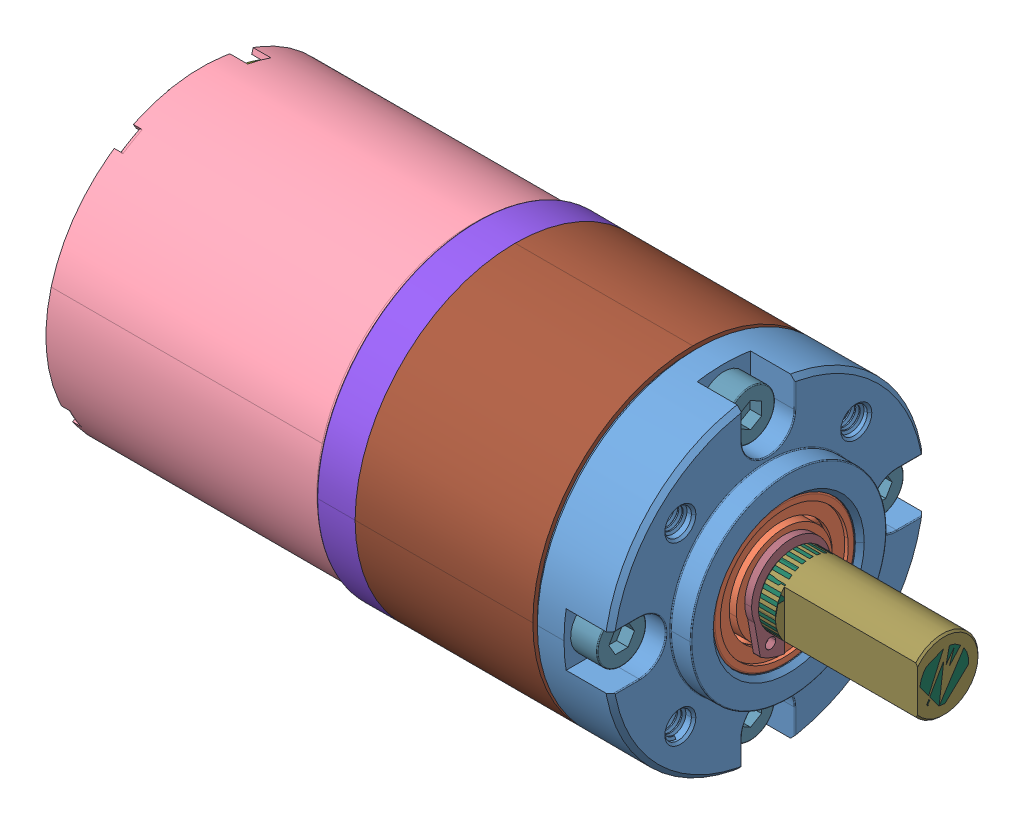
SolidWorks assembly 36GP-3530(L=32.5), configuration 默认. Lengths in mm.
Overall size (89.4 45.32 45.32).
23 component instances, 15 part files, 0 mates.
Components (placement in the parent):
- 36GP-3530(L=32.5).STEP-1: 36GP-3530(L=32.5).STEP [默认] at origin size (89.4 45.32 45.32)
  - 36GP-3530(L=32.5).STEP.STEP-1: 36GP-3530(L=32.5).STEP.STEP [默认] at origin size (89.4 45.32 45.32)
    - ____________.STEP.STEP-1: ____________.STEP.STEP [默认] at (23.768 15.617 71.7536) x (1 0 0) z (0 0 -1) size (12.18 36 36)
      - ____________-0.STEP.STEP-1: ____________-0.STEP.STEP [默认] at (-7.2884 -0.669 36) size (12 36 36)
      - ____628__8-2Z.STEP.STEP-1: ____628__8-2Z.STEP.STEP [默认] at (-4.7884 -0.669 36) x (1 0 0) z (0 -0.111693 0.993743) size (5 16 16)
      - ____628__8-2Z.STEP.STEP-2: ____628__8-2Z.STEP.STEP [默认] at (1.7116 -0.669 36) x (1 0 0) z (0 -0.111693 0.993743) size (5 16 16)
      - ________________.STEP.STEP-1: ________________.STEP.STEP [默认] at (-7.4684 -0.669 36) x (0 -1 0) z (0 0 1) size (12 0.18 12)
    - 3530.STEP.STEP-1: 3530.STEP.STEP [默认] at (-6.6204 16.286 35.7536) x (1 0 0) z (0 0.258819 0.965926) size (45.8 37 37)
      - ______.STEP.STEP-1: ______.STEP.STEP [默认] at origin size (33.5 35 35)
      - ________.STEP.STEP-1: ________.STEP.STEP [默认] at (-21 0 0) x (1 0 0) z (0 -0.107062 0.994252) size (18 33.6 33.6)
      - ________-1.STEP.STEP-1: ________-1.STEP.STEP [默认] at (-17.6 0 0) x (1 0 0) z (0 -0.932296 0.361697) size (40 22.81 23)
      - ____.STEP.STEP-1: ____.STEP.STEP [默认] x (-1 0 0) z (0 0 -1) size (14.84 33.8 33.8)
    - ____________-2.STEP.STEP-1: ____________-2.STEP.STEP [默认] at (-6.6204 16.286 35.7536) size (7.51 36 36)
    - ____________________.STEP.STEP-1: ____________________.STEP.STEP [默认] at (0.8796 16.286 35.7536) x (0 -1 0) z (0 0 1) size (22 0.18 22)
    - ____11__0.5____.STEP.STEP-1: ____11__0.5____.STEP.STEP [默认] at (-1.1204 16.286 35.7536) x (0 -0.997892 0.064895) z (1 0 0) size (6.47 6.41 5.5)
    - ____46__0.5.STEP.STEP-1: ____46__0.5.STEP.STEP [默认] at (-2.3204 16.286 35.7536) x (0 0 -1) z (1 0 0) size (36 36 20)
    - ______________.STEP.STEP-1: ______________.STEP.STEP [默认] at (15.9796 16.286 35.7536) x (0 0 -1) z (1 0 0) size (20.5 20.5 38.5)
    - __________________.STEP.STEP-1: __________________.STEP.STEP [默认] at (28.3666 16.9131 35.7536) x (0 0 1) z (-1 0 0) size (8.9 10.83 0.77)
    - ____M3__40.STEP.STEP-1: ____M3__40.STEP.STEP [默认] at (24.1796 16.286 50.2536) x (-1 0 0) z (0 -0.867883 0.496768) size (41 5.5 5.5)
    - ____M3__40.STEP.STEP-2: ____M3__40.STEP.STEP [默认] at (24.1796 30.786 35.7536) x (-1 0 0) z (0 0.496768 0.867883) size (41 5.5 5.5)
    - ____M3__40.STEP.STEP-3: ____M3__40.STEP.STEP [默认] at (24.1796 16.286 21.2536) x (-1 0 0) z (0 0.867883 -0.496768) size (41 5.5 5.5)
    - ____M3__40.STEP.STEP-4: ____M3__40.STEP.STEP [默认] at (24.1796 1.786 35.7536) x (-1 0 0) z (0 -0.496768 -0.867883) size (41 5.5 5.5)
  - abc.STEP-1: abc.STEP [默认] at (15.9796 16.286 35.7536) x (0 -0.924225 -0.381849) z (1 0 0) size (20.5 20.5 38.5)
